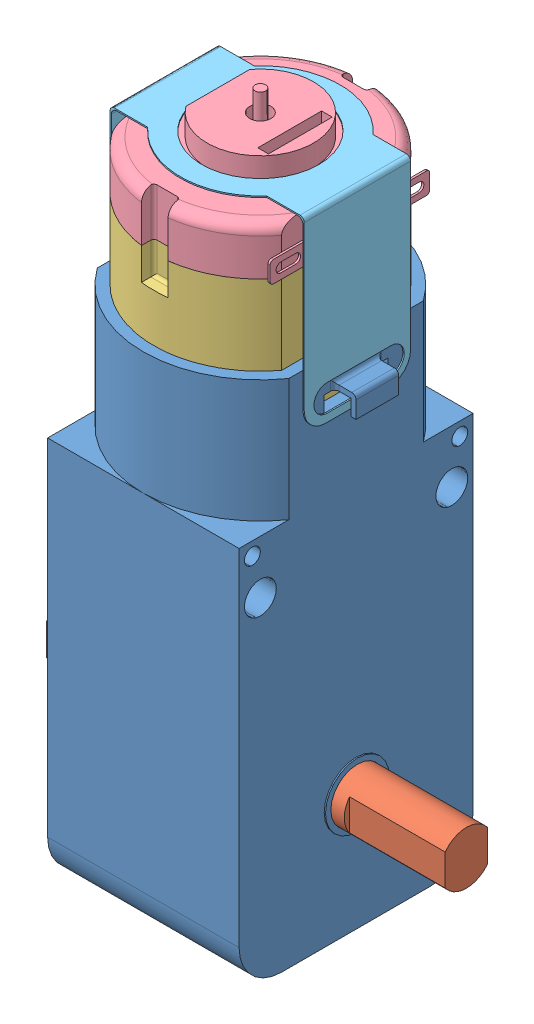
SolidWorks assembly Yellow__Gearbox__Motor, configuration Default. Lengths in mm.
Overall size (37.5 69 22).
5 component instances, 5 part files, 12 mates.
Components (placement in the parent):
- Gearbox__Base-1: Gearbox__Base [Default] at origin size (22 53 22)
- Gearbox__Shaft-1: Gearbox__Shaft [Default] at (3.875 11 0) x (0 0.001927 0.999998) z (-1 0 0) size (4.96 4.96 37.5)
- CC__Motor__Base-1: CC__Motor__Base [Default] at (0 36.5 0) x (-1 0 0) z (0 0 -1) size (16 19 20)
- CC__Motor__Cover-1: CC__Motor__Cover [Default] at (0 55.5 0) x (-1 0 0) z (0 0 -1) size (16.77 8.5 19.96)
- CC__Motor__Attach-1: CC__Motor__Attach [Default] at (0 60.375 0) x (0 0 1) z (-1 0 0) size (15 17.75 18.25)
Mates (geometry in assembly coordinates):
- Coincident1: coordinate: point of Gearbox__Base-1
- Concentric1: concentric aligned: cylinder of Gearbox__Base-1 through (11 11 0) axis (-1 0 0) radius 2.5; circle of Gearbox__Shaft-1
- Coincident2: coincident aligned: plane of Gearbox__Base-1 through (-9.125 0 0) normal (-1 0 0); plane of Gearbox__Shaft-1 through (-9.125 11 0) normal (-1 0 0)
- Coincident3: coincident anti-aligned: plane of CC__Motor__Base-1 through (0 55.5 0) normal (0 1 0); plane of CC__Motor__Cover-1 through (0 55.5 0) normal (0 -1 0)
- Coincident4: coincident aligned: line of CC__Motor__Base-1 through (-8 55.5 -6) axis (0 0 1); line of CC__Motor__Cover-1 through (-8 55.5 -6) axis (0 0 1)
- Coincident5: coincident aligned: circle of CC__Motor__Base-1; circle of CC__Motor__Cover-1
- Coincident6: coincident anti-aligned: plane of Gearbox__Base-1 through (0 36.5 0) normal (0 1 0); plane of CC__Motor__Base-1 through (0 36.5 0) normal (0 -1 0)
- Coincident8: coincident anti-aligned: plane of Gearbox__Base-1 through (8 48 6) normal (-1 0 0); plane of CC__Motor__Base-1 through (8 55.5 -6) normal (1 0 0)
- Concentric3: concentric aligned: cylinder of Gearbox__Base-1 through (0 48 0) axis (0 -1 0) radius 10; cylinder of CC__Motor__Base-1 through (0 55.5 0) axis (0 -1 0) radius 10
- Concentric4: concentric aligned: cylinder of CC__Motor__Cover-1 through (0 62 0) axis (0 -1 0) radius 5; cylinder of CC__Motor__Attach-1 through (0 60.5 0) axis (0 -1 0) radius 5.5
- Coincident10: coincident anti-aligned: plane of Gearbox__Base-1 through (9 36.5 -11) normal (1 0 0); plane of CC__Motor__Attach-1 through (9 60.5 -7.8835) normal (-1 0 0)
- Coincident13: coincident aligned: plane of Gearbox__Base-1 through (-5 43.5 -3) normal (0 1 0); plane of CC__Motor__Attach-1 through (0 43.5 -3.1569) normal (0 1 0)
